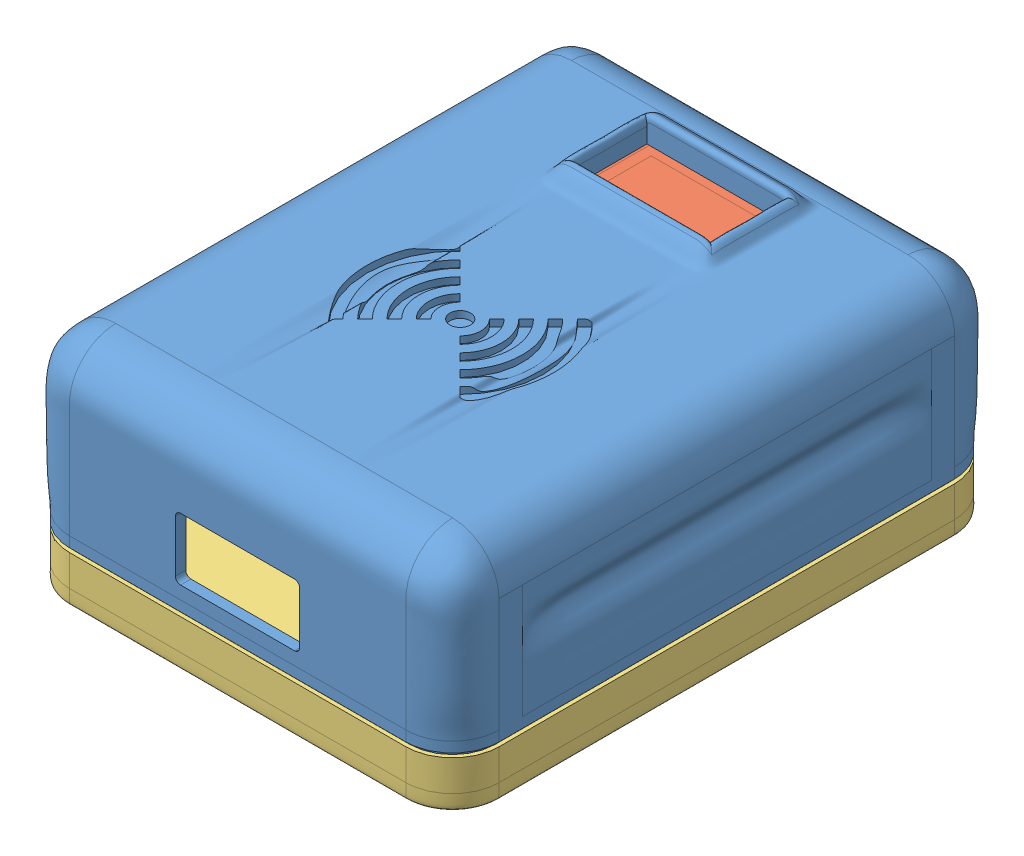
SolidWorks assembly FinalAssembly, configuration Default. Lengths in mm.
Overall size (83.42 45.85 106.27).
3 component instances, 3 part files, 6 mates.
Components (placement in the parent):
- Base-1: Base [Default] at (-10.9526 25.541 85.9293) x (1 0 0) z (0 0 -1) size (83.42 38.4 106.27)
- PCB_New-1: PCB_New [Default] at (46.8694 134.5442 137.959) x (-1 0 0) z (0 -1 0) size (70.48 93.47 35.57)
- Cover-1: Cover [Default] at (-10.9526 25.741 85.9293) x (1 0 0) z (0 0 -1) size (83.03 9.02 106.03)
Mates (geometry in assembly coordinates):
- Concentric1: concentric: circle of Base-1; circle of PCB_New-1
- Concentric2: concentric: circle of Base-1; circle of PCB_New-1
- Coincident3: coincident anti-aligned: plane of Base-1 through (30.5477 66.541 65.2242) normal (0 -1 0); plane of PCB_New-1 through (30.5474 66.541 56.9838) normal (0 1 0)
- Concentric3: concentric: circle of Base-1; circle of Cover-1
- Concentric4: concentric: circle of Base-1; circle of Cover-1
- Coincident4: coincident anti-aligned: plane of Base-1 through (-11.1722 33.241 141.4845) normal (0 -1 0); plane of Cover-1 through (-11.1722 33.241 141.4845) normal (0 1 0)
